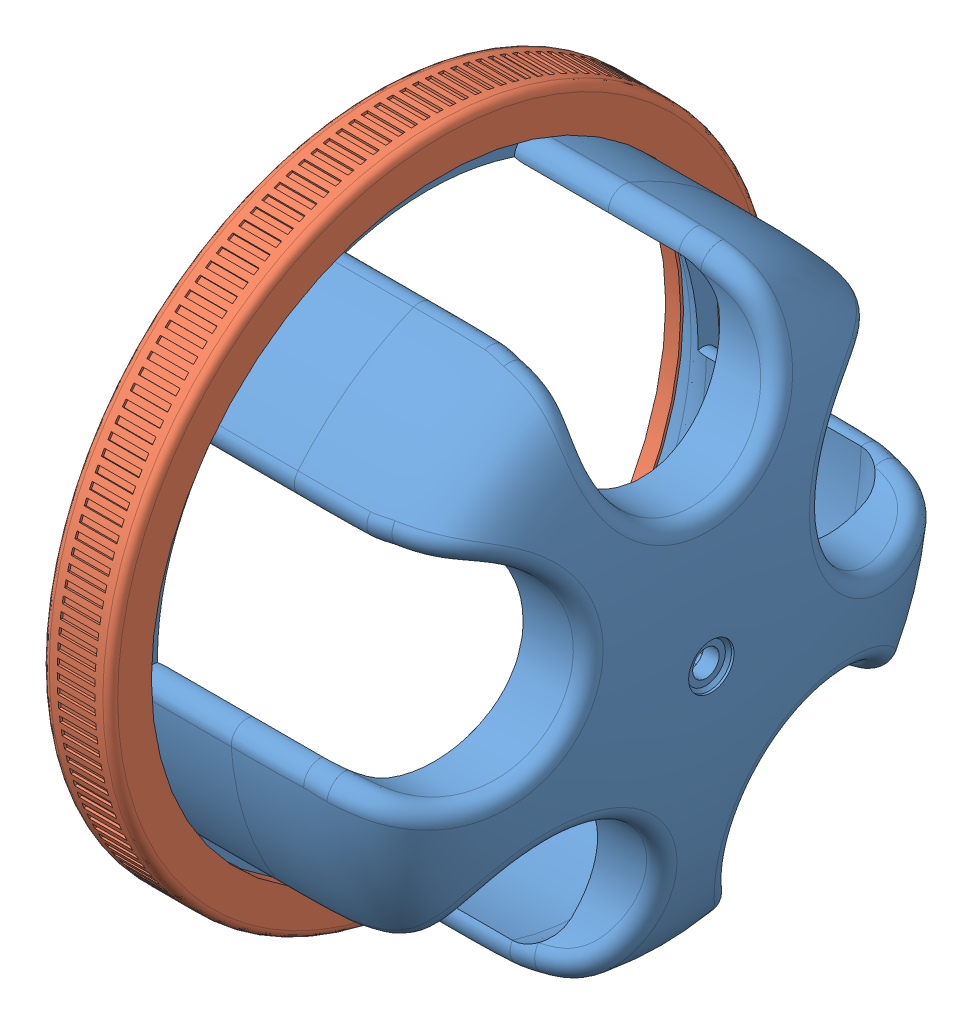
SolidWorks assembly Assem_wheel01, configuration Default. Lengths in mm.
Overall size (43.39 85 85).
2 component instances, 2 part files, 2 mates.
Components (placement in the parent):
- SD-207 EduRover Wheel-1: SD-207 EduRover Wheel [Default] at (-0.8067 39.7572 71.1423) size (43.07 81.4 81.4)
- Pololu 90mm Tire-1: Pololu 90mm Tire [Default] at (-0.0111 39.7572 71.1423) size (8.75 85 85)
Mates (geometry in assembly coordinates):
- Concentric1: concentric: cylinder of SD-207 EduRover Wheel-1 through (-1000.6779 39.7572 71.1423) axis (-1 0 0) radius 40.7; cylinder of Pololu 90mm Tire-1 through (-1000.0111 39.7572 71.1423) axis (-1 0 0) radius 40.7
- Coincident1: coincident: plane of SD-207 EduRover Wheel-1 through (2.4433 76.9572 71.1423) normal (1 0 0); plane of Pololu 90mm Tire-1 through (2.4433 79.6572 71.1423) normal (-1 0 0)
